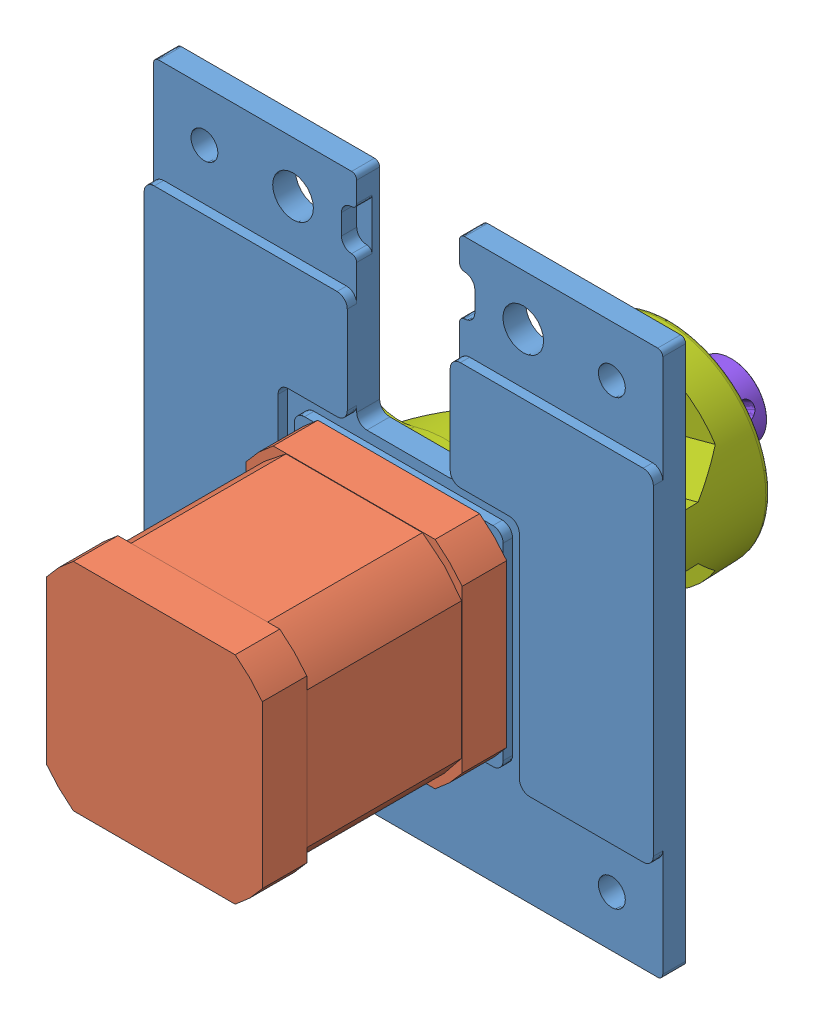
SolidWorks assembly machined_back_z_motor_plate_assy, configuration Default. Lengths in mm.
Overall size (100 107 113.35).
18 component instances, 10 part files, 5 mates.
Components (placement in the parent):
- machined_back_z_motor_plate-1: machined_back_z_motor_plate [Back] at origin size (100 107 6.35)
- z-motor_thrust_assembly-1: z-motor_thrust_assembly [Default] at origin size (42.42 42.42 113.35)
  - 17HM19-2004S-1: 17HM19-2004S [Default] at (0 -11.5 6.35) x (1 0 0) z (0 0 -1) size (42.42 42.42 72)
  - AST_Bearings_F8-19M-1: AST_Bearings_F8-19M [Default] at (-0.0375 -11.4625 -48.5) x (1 0 0) z (0 1 0) size (19 7 19)
  - couplings_cajc20-rd-5-8-1: couplings_cajc20-rd-5-8 [Default] at (0 -11.5 -22.65) x (0 0 -1) z (1 0 0) size (30 20 20)
    - couplings_cajc20-rd-5-8_01-1: couplings_cajc20-rd-5-8_01 [Default] at origin size (8 18.12 18.12)
    - couplings_cajc20-rd-5-8_02-1: couplings_cajc20-rd-5-8_02 [Default] at origin size (19 20 19.99)
    - couplings_cajc20-rd-5-8_03-1: couplings_cajc20-rd-5-8_03 [Default] at origin size (19 19.99 20)
  - thrust_cage-1: thrust_cage [Default] at (-0.0375 -11.4625 -15.6528) x (1 0 0) z (0 1 0) size (42.3 47 42.3)
  - T8_lock_collar-1: T8_lock_collar [Default] at (-0.0375 -11.4625 -59) x (0 1 0) z (1 0 0) size (14 7 14)
  - m3_stainless_steel_washer_90965A130-1: m3_stainless_steel_washer_90965A130 [90965A130] at (15.5 4 -3) x (0.923728 0.383049 0) z (0 0 -1) size (7 7 0.6)
  - m3_12mm_buttohead_screw_92095A183-1: m3_12mm_buttohead_screw_92095A183 [92095A183] at (15.5 4 -5.25) x (0.923728 0.383049 0) z (0 0 -1) size (5.7 5.7 13.97)
  - m3_stainless_steel_washer_90965A130-2: m3_stainless_steel_washer_90965A130 [90965A130] at (-15.5 4 -3) x (0.923728 0.383049 0) z (0 0 -1) size (7 7 0.6)
  - m3_stainless_steel_washer_90965A130-3: m3_stainless_steel_washer_90965A130 [90965A130] at (15.5 -27 -3) x (0.923728 0.383049 0) z (0 0 -1) size (7 7 0.6)
  - m3_stainless_steel_washer_90965A130-4: m3_stainless_steel_washer_90965A130 [90965A130] at (-15.5 -27 -3) x (0.923728 0.383049 0) z (0 0 -1) size (7 7 0.6)
  - m3_12mm_buttohead_screw_92095A183-2: m3_12mm_buttohead_screw_92095A183 [92095A183] at (15.5 -27 -5.25) x (0.923728 0.383049 0) z (0 0 -1) size (5.7 5.7 13.97)
  - m3_12mm_buttohead_screw_92095A183-3: m3_12mm_buttohead_screw_92095A183 [92095A183] at (-15.5 -27 -5.25) x (0.923728 0.383049 0) z (0 0 -1) size (5.7 5.7 13.97)
  - m3_12mm_buttohead_screw_92095A183-5: m3_12mm_buttohead_screw_92095A183 [92095A183] at (-15.5 4 -5.25) x (0.923728 0.383049 0) z (0 0 -1) size (5.7 5.7 13.97)
Mates (geometry in assembly coordinates):
- Coincident6: coincident anti-aligned: plane of machined_back_z_motor_plate-1 through (0 0 6.35) normal (0 0 1); plane of Assem2^machined_back_z_motor_plate_assy-1/17HM19-2004S-1 through (0 -11.5 6.35) normal (0 0 -1)
- Concentric7: concentric aligned: cylinder of machined_back_z_motor_plate-1 through (0 -11.5 0) axis (0 0 1) radius 12.5; cylinder of Assem2^machined_back_z_motor_plate_assy-1/17HM19-2004S-1 through (0 -11.5 4.35) axis (0 0 1) radius 11
- Concentric8: concentric anti-aligned: circle of machined_back_z_motor_plate-1; circle of Assem2^machined_back_z_motor_plate_assy-1/thrust_cage-1
- Concentric9: concentric anti-aligned: circle of machined_back_z_motor_plate-1; circle of Assem2^machined_back_z_motor_plate_assy-1/thrust_cage-1
- Coincident7: coincident anti-aligned: plane of machined_back_z_motor_plate-1 through (0 0 0) normal (0 0 -1); plane of Assem2^machined_back_z_motor_plate_assy-1/thrust_cage-1 through (-0.0375 -11.4625 0) normal (0 0 1)
